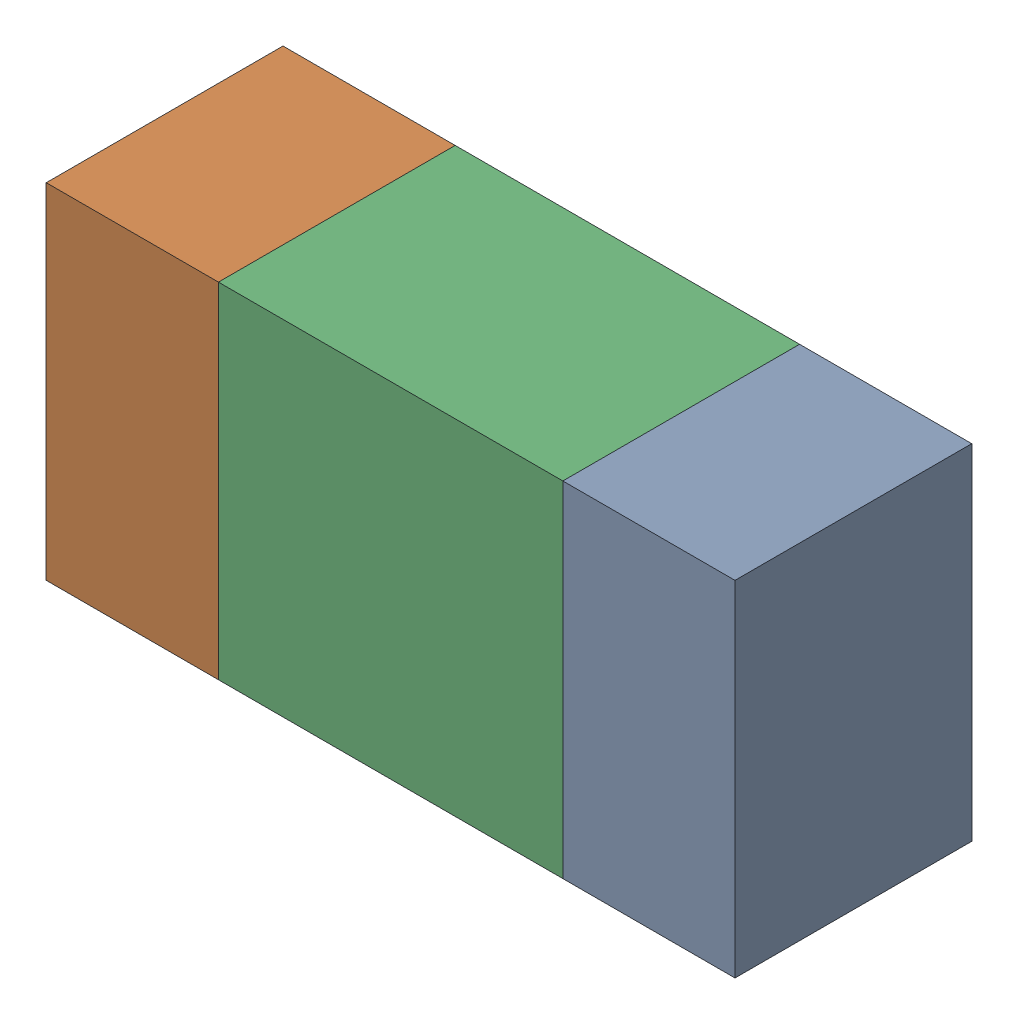
SolidWorks assembly R23, configuration ﾃﾞﾌｫﾙﾄ. Lengths in mm.
Overall size (1.6 0.8 0.55).
6 component instances, 2 part files, 0 mates.
Components (placement in the parent):
- 689261512-1: 689261512 [ﾃﾞﾌｫﾙﾄ] at (6.3149 20.6376 -1.7503) size (0.4 0.8 0.55)
  - Extruded_32-1: Extruded_32 [ﾃﾞﾌｫﾙﾄ] at origin size (0.4 0.8 0.55)
- 689261512-2: 689261512 [ﾃﾞﾌｫﾙﾄ] at (5.1149 20.6376 -1.7503) size (0.4 0.8 0.55)
  - Extruded_32-1: Extruded_32 [ﾃﾞﾌｫﾙﾄ] at origin size (0.4 0.8 0.55)
- 689261648-1: 689261648 [ﾃﾞﾌｫﾙﾄ] at (5.715 20.6376 -1.7503) size (0.8 0.8 0.55)
  - Extruded_33-1: Extruded_33 [ﾃﾞﾌｫﾙﾄ] at origin size (0.8 0.8 0.55)
